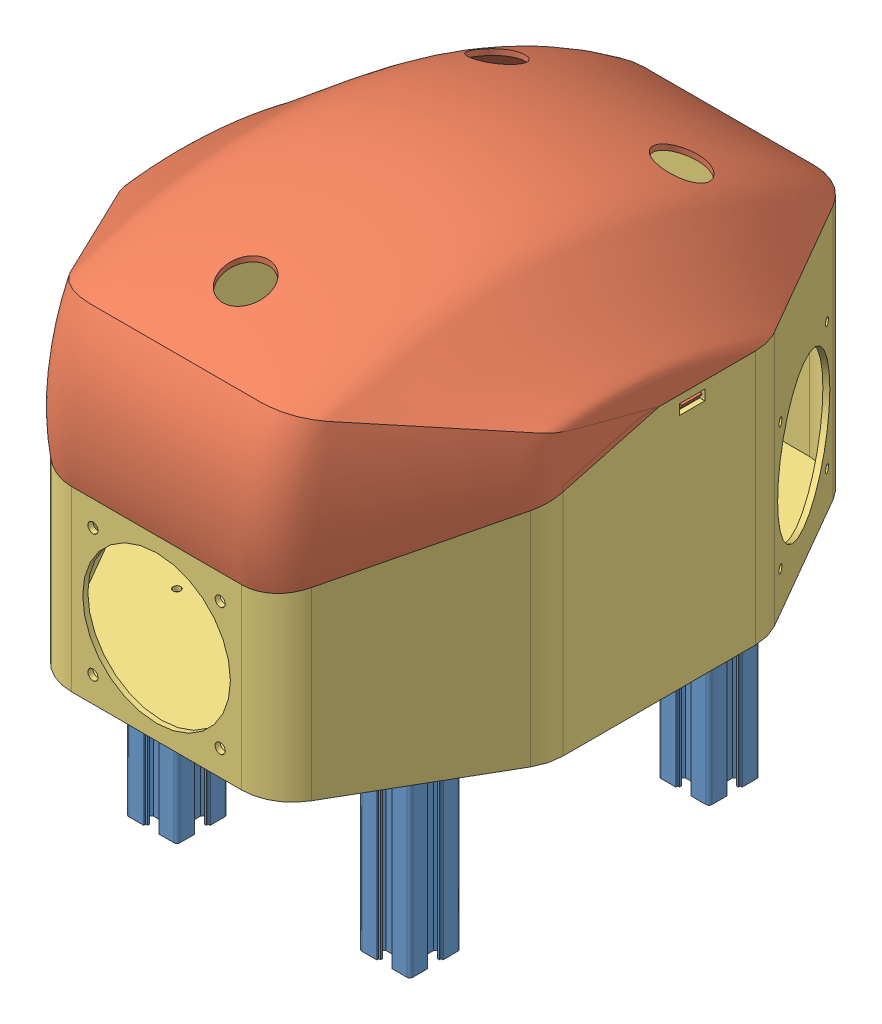
SolidWorks assembly gazebo_box, configuration Predeterminado. Lengths in mm.
Overall size (174.79 238.19 229.98).
6 component instances, 3 part files, 17 mates.
Components (placement in the parent):
- 2020_180mm-1: 2020_180mm [Valor predeterminado] at (45.75 -37.5 -58.75) x (1 0 0) z (0 -1 0) size (20 20 75)
- head_cover-1: head_cover [Predeterminado] at (0 100 0) size (174.79 93.34 229.98)
- Box_half-1: Box_half [Predeterminado] at origin size (170 100 225)
- 2020_180mm-2: 2020_180mm [Valor predeterminado] at (45.75 -37.5 58.75) x (1 0 0) z (0 -1 0) size (20 20 75)
- 2020_180mm-3: 2020_180mm [Valor predeterminado] at (-45.75 -37.5 -58.75) x (1 0 0) z (0 -1 0) size (20 20 75)
- 2020_180mm-4: 2020_180mm [Valor predeterminado] at (-45.75 -37.5 58.75) x (1 0 0) z (0 -1 0) size (20 20 75)
Mates (geometry in assembly coordinates):
- Coincidente1: coincident aligned: plane of Box_half-1 through (0 0 0) normal (0 1 0); plane of assembly through (0 0 0) normal (0 1 0)
- Coincidente2: coincident aligned: plane of Box_half-1 through (0 0 0) normal (0 0 1); plane of assembly through (0 0 0) normal (0 0 1)
- Coincidente3: coincident aligned: plane of Box_half-1 through (0 0 0) normal (1 0 0); plane of assembly through (0 0 0) normal (1 0 0)
- Coincidente4: coincident anti-aligned: plane of head_cover-1 through (83 69.8557 37.859) normal (1 0 0); plane of Box_half-1 through (83 100 -37.859) normal (-1 0 0)
- Coincidente5: coincident anti-aligned: plane of head_cover-1 through (33.453 69.8557 -110.5) normal (0 0 -1); plane of Box_half-1 through (-33.453 100 -110.5) normal (0 0 1)
- Coincidente6: coincident anti-aligned: plane of head_cover-1 through (-85.005 100 0) normal (0 -1 0); plane of Box_half-1 through (65 100 -37.859) normal (0 1 0)
- Concéntrica1: concentric anti-aligned: circle of 2020_180mm-1; circle of Box_half-1
- Coincidente7: coincident anti-aligned: plane of 2020_180mm-1 through (45.75 0 -58.75) normal (0 1 0); plane of Box_half-1 through (65 0 -37.859) normal (0 -1 0)
- Concéntrica2: concentric anti-aligned: circle of Box_half-1; circle of 2020_180mm-3
- Coincidente9: coincident anti-aligned: plane of Box_half-1 through (65 0 -37.859) normal (0 -1 0); plane of 2020_180mm-3 through (-45.75 0 -58.75) normal (0 1 0)
- Paralelo2: parallel aligned: plane of 2020_180mm-1 through (35.75 -75 -58.75) normal (-1 0 0); plane of 2020_180mm-3 through (-55.75 -75 -58.75) normal (-1 0 0)
- Concéntrica3: concentric anti-aligned: circle of Box_half-1; circle of 2020_180mm-4
- Coincidente11: coincident aligned: plane of 2020_180mm-3 through (-55.75 -75 -58.75) normal (-1 0 0); plane of 2020_180mm-4 through (-55.75 -75 58.75) normal (-1 0 0)
- Coincidente12: coincident anti-aligned: plane of Box_half-1 through (65 0 -37.859) normal (0 -1 0); plane of 2020_180mm-4 through (-45.75 0 58.75) normal (0 1 0)
- Concéntrica4: concentric anti-aligned: circle of Box_half-1; circle of 2020_180mm-2
- Coincidente13: coincident aligned: plane of 2020_180mm-1 through (55.75 -75 -58.75) normal (1 0 0); plane of 2020_180mm-2 through (55.75 -75 58.75) normal (1 0 0)
- Coincidente14: coincident anti-aligned: plane of Box_half-1 through (65 0 -37.859) normal (0 -1 0); plane of 2020_180mm-2 through (45.75 0 58.75) normal (0 1 0)
